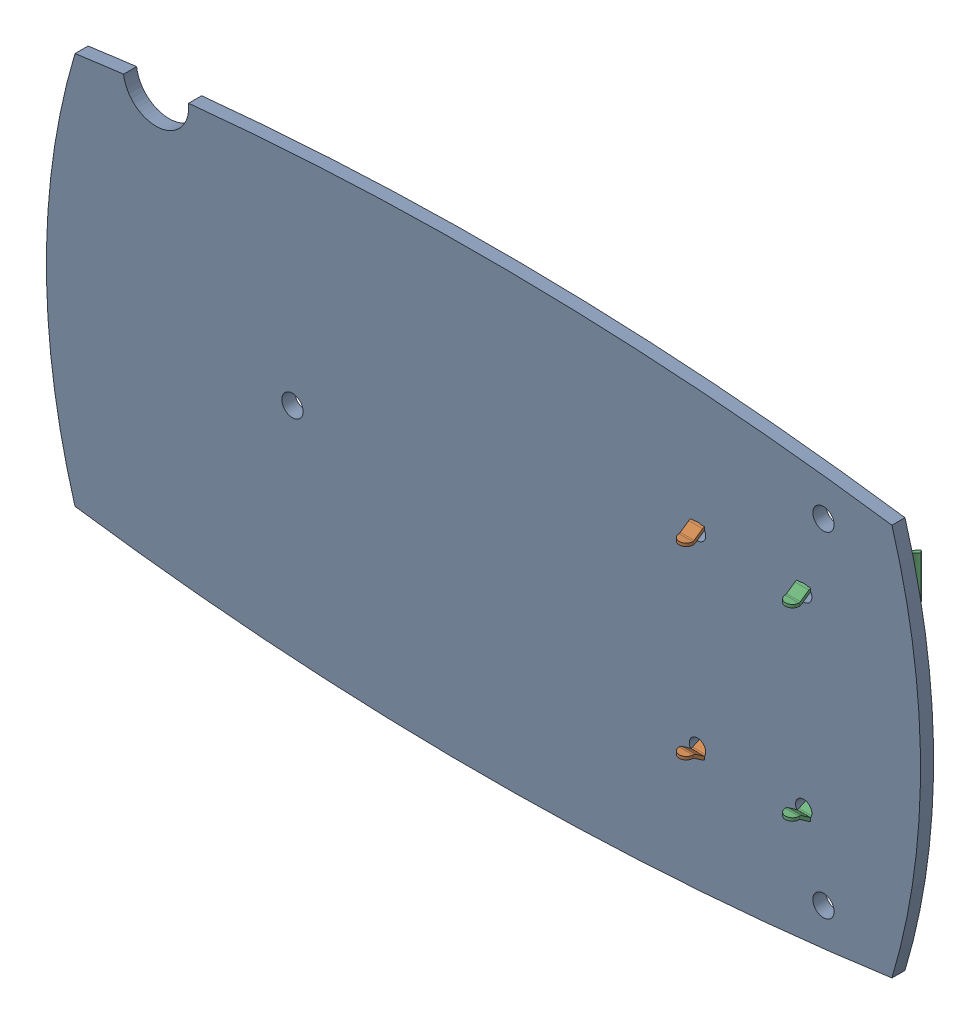
SolidWorks assembly _PLATINE_DUMMY_KOMPLETT-NEU_1, configuration Default. Lengths in mm.
Overall size (107 55 13.93).
5 component instances, 3 part files, 0 mates.
Components (placement in the parent):
- 071-905_RAISONANCE-Dummy-Platine_1-1: 071-905_RAISONANCE-Dummy-Platine_1 [Default] at origin size (107 55 1.6)
- Sicherungshalter_1-1: Sicherungshalter_1 [Default] at (76.2 0 0) x (0 -1 0) z (1 0 0) size (24.76 13.63 6.5)
- Sicherungshalter_1-2: Sicherungshalter_1 [Default] at (89.2 0 0) x (0 -1 0) z (1 0 0) size (24.76 13.63 6.5)
- Schmelzsicherung 5x20_1-1: Schmelzsicherung 5x20_1 [Default] at (76.2 0 -6.5665) x (0.550409 0 -0.834895) z (0 1 0) size (5.1 5.1 20)
- Schmelzsicherung 5x20_1-2: Schmelzsicherung 5x20_1 [Default] at (89.2 0 -6.5665) x (-0.333916 0 -0.942603) z (0 1 0) size (5.1 5.1 20)
